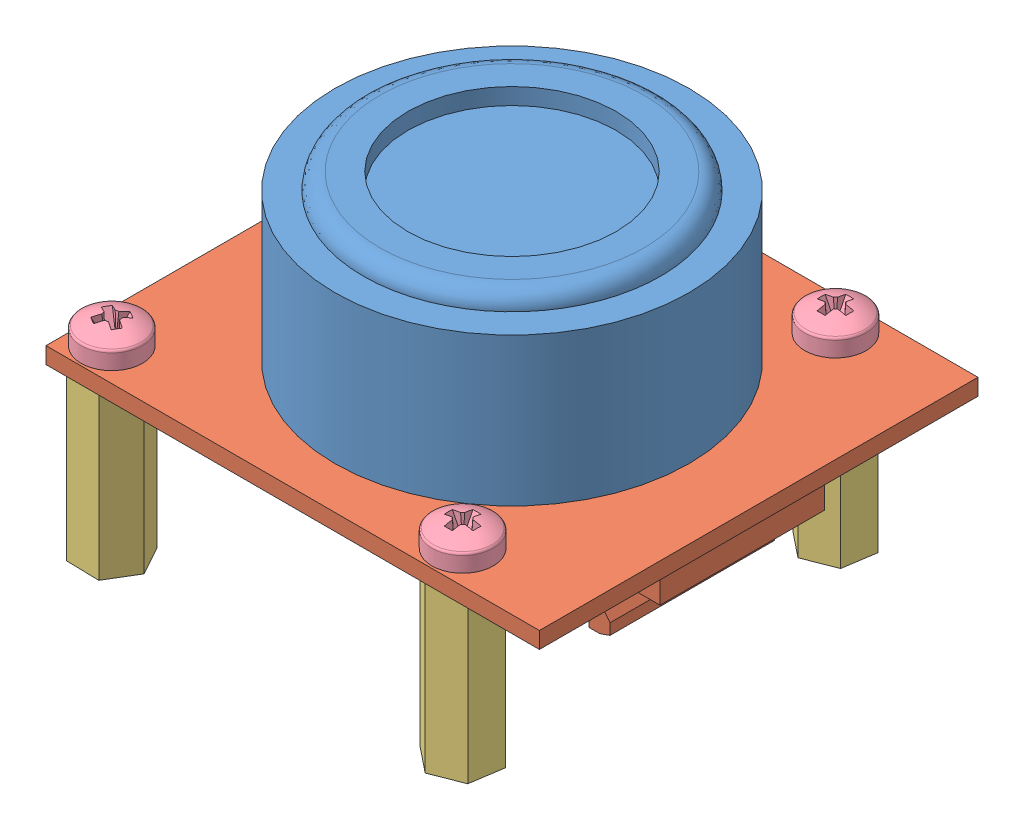
SolidWorks assembly SensorFull, configuration Default. Lengths in mm.
Overall size (45.84 31.5 40.84).
10 component instances, 4 part files, 19 mates.
Components (placement in the parent):
- Sensor-1: Sensor [Default] at (23.8863 42.9826 49.0124) size (32.3 16.5 32.3)
- Sensor Plate-1: Sensor Plate [Default] at (23.8863 26.4826 49.0124) x (-1 0 0) z (0 0 1) size (45 10 40)
- Plate Screwtop-1: Plate Screwtop [Default] at (4.3863 26.4826 66.0124) x (0.924291 0 0.38169) z (-0.38169 0 0.924291) size (5.59 15 5.93)
- Plate Screwtop-2: Plate Screwtop [Default] at (36.3863 26.4826 66.0124) size (5.59 15 5.93)
- Plate Screwtop-3: Plate Screwtop [Default] at (36.3863 26.4826 32.0124) size (5.59 15 5.93)
- Plate Screwtop-4: Plate Screwtop [Default] at (4.3863 26.4826 32.0124) size (5.59 15 5.93)
- pan head cross recess screw_bsi-1: pan head cross recess screw_bsi [ISO 7045 - M3 x 10 - Z --- 10S] at (4.3863 30.3826 66.0124) x (0 -1 0) z (-0.510495 0 0.859881) size (12.35 5.6 5.6)
- pan head cross recess screw_bsi-2: pan head cross recess screw_bsi [ISO 7045 - M3 x 10 - Z --- 10S] at (4.3863 30.3826 32.0124) x (0 -1 0) z (0 0 1) size (12.35 5.6 5.6)
- pan head cross recess screw_bsi-3: pan head cross recess screw_bsi [ISO 7045 - M3 x 10 - Z --- 10S] at (36.3863 30.3826 32.0124) x (0 -1 0) z (0 0 1) size (12.35 5.6 5.6)
- pan head cross recess screw_bsi-4: pan head cross recess screw_bsi [ISO 7045 - M3 x 10 - Z --- 10S] at (36.3863 30.3826 66.0124) x (0 -1 0) z (0 0 1) size (12.35 5.6 5.6)
Mates (geometry in assembly coordinates):
- Coincident1: coincident aligned: plane of Sensor-1 through (23.8863 26.4826 49.0124) normal (0 -1 0); plane of Sensor Plate-1 through (23.8863 26.4826 49.0124) normal (0 -1 0)
- Concentric3: concentric aligned: cylinder of Sensor-1 through (23.8863 28.9826 57.5124) axis (0 -1 0) radius 1.4; cylinder of Sensor Plate-1 through (23.8863 27.9826 57.5124) axis (0 -1 0) radius 1.4
- Concentric6: concentric aligned: cylinder of Sensor-1 through (17.8759 28.9826 43.002) axis (0 -1 0) radius 1.4; cylinder of Sensor Plate-1 through (17.8759 27.9826 43.002) axis (0 -1 0) radius 1.4
- Coincident2: coincident anti-aligned: plane of Sensor Plate-1 through (23.8863 26.4826 49.0124) normal (0 -1 0); plane of Plate Screwtop-1 through (4.3863 26.4826 66.0124) normal (0 1 0)
- Concentric7: concentric anti-aligned: cylinder of Sensor Plate-1 through (4.3863 27.9826 66.0124) axis (0 -1 0) radius 1.5; cylinder of Plate Screwtop-1 through (4.3863 11.4826 66.0124) axis (0 1 0) radius 1.5
- Coincident3: coincident anti-aligned: plane of Sensor Plate-1 through (23.8863 26.4826 49.0124) normal (0 -1 0); plane of Plate Screwtop-2 through (36.3863 26.4826 66.0124) normal (0 1 0)
- Concentric8: concentric anti-aligned: cylinder of Sensor Plate-1 through (36.3863 27.9826 66.0124) axis (0 -1 0) radius 1.5; cylinder of Plate Screwtop-2 through (36.3863 11.4826 66.0124) axis (0 1 0) radius 1.5
- Coincident4: coincident anti-aligned: plane of Sensor Plate-1 through (23.8863 26.4826 49.0124) normal (0 -1 0); plane of Plate Screwtop-3 through (36.3863 26.4826 32.0124) normal (0 1 0)
- Concentric9: concentric anti-aligned: cylinder of Sensor Plate-1 through (36.3863 27.9826 32.0124) axis (0 -1 0) radius 1.5; cylinder of Plate Screwtop-3 through (36.3863 11.4826 32.0124) axis (0 1 0) radius 1.5
- Coincident5: coincident anti-aligned: plane of Sensor Plate-1 through (23.8863 26.4826 49.0124) normal (0 -1 0); plane of Plate Screwtop-4 through (4.3863 26.4826 32.0124) normal (0 1 0)
- Concentric10: concentric anti-aligned: cylinder of Sensor Plate-1 through (4.3863 27.9826 32.0124) axis (0 -1 0) radius 1.5; cylinder of Plate Screwtop-4 through (4.3863 11.4826 32.0124) axis (0 1 0) radius 1.5
- Coincident6: coincident anti-aligned: plane of Sensor Plate-1 through (23.8863 27.9826 49.0124) normal (0 1 0); plane of pan head cross recess screw_bsi-1 through (5.6762 27.9826 66.7781) normal (0 -1 0)
- Coincident7: coincident anti-aligned: cylinder of Sensor Plate-1 through (4.3863 27.9826 66.0124) axis (0 -1 0) radius 1.5; circle of pan head cross recess screw_bsi-1
- Coincident8: coincident anti-aligned: plane of Sensor Plate-1 through (23.8863 27.9826 49.0124) normal (0 1 0); plane of pan head cross recess screw_bsi-4 through (37.8863 27.9826 66.0124) normal (0 -1 0)
- Coincident9: coincident anti-aligned: cylinder of Sensor Plate-1 through (36.3863 27.9826 66.0124) axis (0 -1 0) radius 1.5; circle of pan head cross recess screw_bsi-4
- Coincident10: coincident anti-aligned: plane of Sensor Plate-1 through (23.8863 27.9826 49.0124) normal (0 1 0); plane of pan head cross recess screw_bsi-2 through (5.8863 27.9826 32.0124) normal (0 -1 0)
- Coincident11: coincident anti-aligned: cylinder of Sensor Plate-1 through (4.3863 27.9826 32.0124) axis (0 -1 0) radius 1.5; circle of pan head cross recess screw_bsi-2
- Coincident12: coincident anti-aligned: plane of Sensor Plate-1 through (23.8863 27.9826 49.0124) normal (0 1 0); plane of pan head cross recess screw_bsi-3 through (37.8863 27.9826 32.0124) normal (0 -1 0)
- Coincident13: coincident anti-aligned: cylinder of Sensor Plate-1 through (36.3863 27.9826 32.0124) axis (0 -1 0) radius 1.5; circle of pan head cross recess screw_bsi-3
